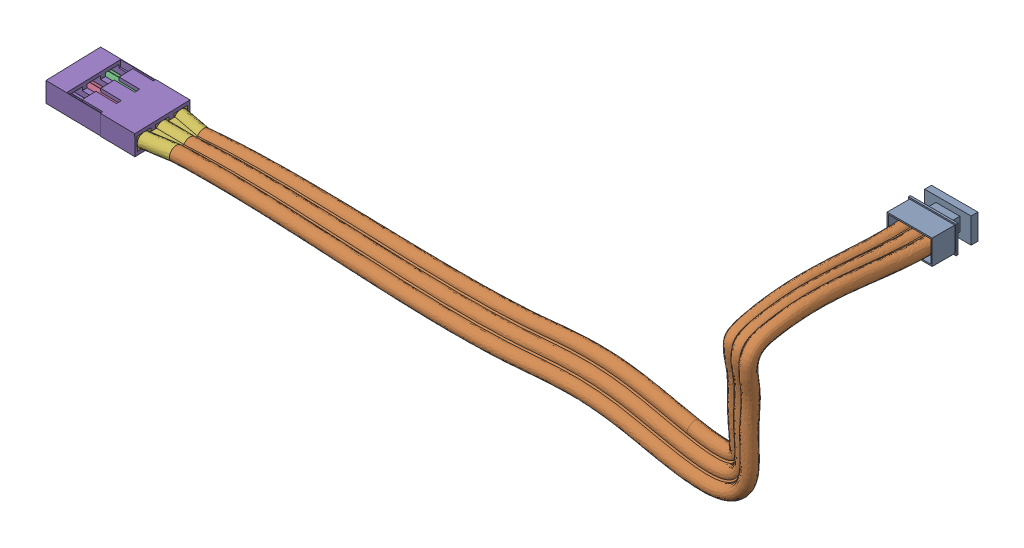
SolidWorks assembly filo completo 1, configuration Default. Lengths in mm.
Overall size (101.46 24.77 35.07).
4 component instances, 4 part files, 10 mates.
Components (placement in the parent):
- Connettore servom-3: Connettore servom [Default] at (4.831 6.0071 -0.15) x (0 -1 0) z (0 0 -1) size (4 7 6.6)
- filo1-1: filo1 [Default] at (1.331 4.0071 -0.15) size (84.46 24.77 30.96)
- Connettore fili-1: Connettore fili [Default] at (-92.6226 -13.5581 27.4769) x (-0.001612 0.029363 -0.999568) z (0.018896 0.999391 0.029327) size (8.1 13 3)
- terminale fili-1: terminale fili [Default] at (-83.6088 -13.3366 31.1705) x (-0.001612 0.029363 -0.999568) z (0.99982 -0.018841 -0.002166) size (7.41 2.02 5.7)
Mates (geometry in assembly coordinates):
- Coincidente14: coincident: point of filo2-1
- Coincidente16: coincident: unknown of filo2-1
- Coincidente18: coincident anti-aligned: plane of Connettore servom-3 through (4.831 6.0071 -0.15) normal (0 0 1); plane of filo2-1 through (1.331 4.0071 -0.15) normal (0 0 -1)
- Coincidente19: coincident anti-aligned: line of filo2-1 through (-79.5853 -11.8375 28.6409) axis (-0.001612 0.029363 -0.999568); line of terminale fili-1 through (-79.5857 -11.8296 28.373) axis (0.001612 -0.029363 0.999568)
- Coincidente20: coincident anti-aligned: line of filo2-1 through (-79.6079 -12.7703 26.3446) axis (0.001612 -0.029363 0.999568); line of terminale fili-1 through (-79.6074 -12.7782 26.6124) axis (-0.001612 0.029363 -0.999568)
- Tangente2: tangent: curve of filo2-1; circle of terminale fili-1
- Coincidente22: coincident anti-aligned: plane of Connettore fili-1 through (-96.5687 -11.0929 31.2573) normal (-0.001612 0.029363 -0.999568); plane of terminale fili-1 through (-85.3085 -13.3045 31.1741) normal (0.001612 -0.029363 0.999568)
- Coincidente23: coincident anti-aligned: plane of Connettore fili-1 through (-96.5687 -11.0929 31.2573) normal (-0.001612 0.029363 -0.999568); plane of terminale fili-1 through (-85.3085 -13.3045 31.1741) normal (0.001612 -0.029363 0.999568)
- Coincidente24: coincident aligned: line of Connettore fili-1 through (-83.6088 -13.3366 31.1705) axis (-0.001612 0.029363 -0.999568); line of terminale fili-1 through (-83.6088 -13.3366 31.1705) axis (-0.001612 0.029363 -0.999568)
- Coincidente26: coincident aligned: line of Connettore fili-1 through (-83.5742 -11.2791 29.23) axis (0.001612 -0.029363 0.999568); line of terminale fili-1 through (-83.5726 -11.3084 30.2304) axis (0.001612 -0.029363 0.999568)
